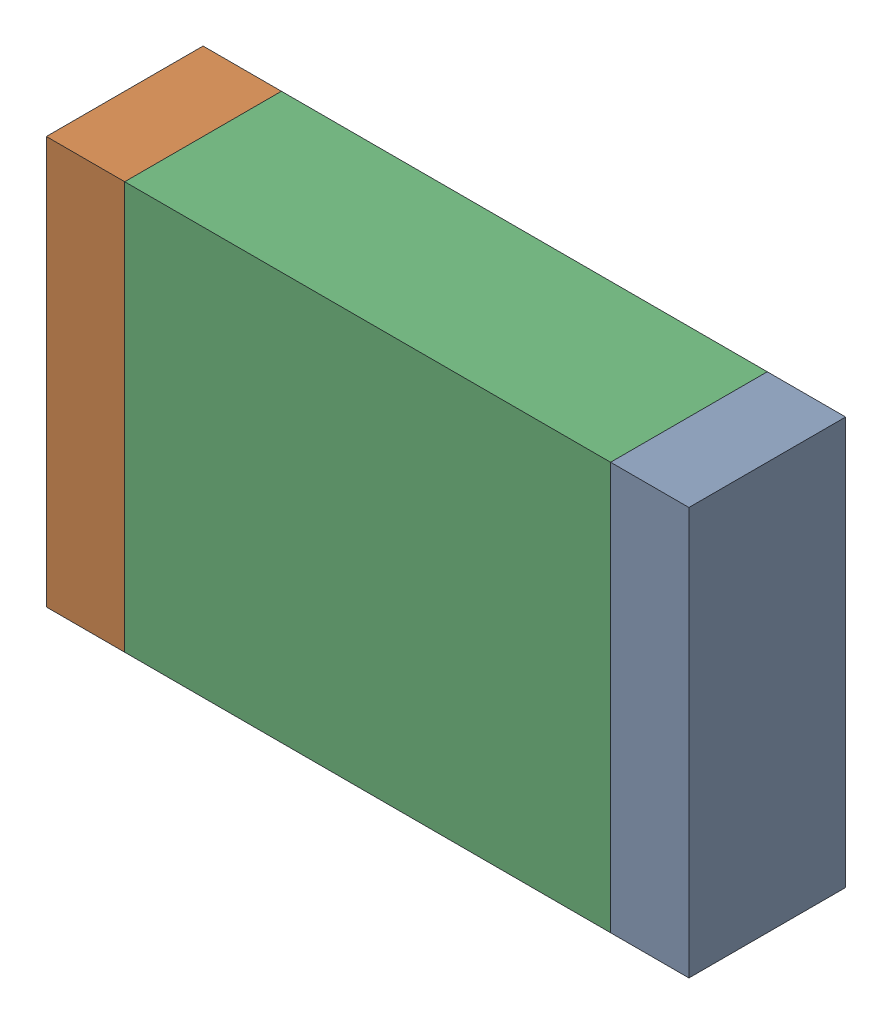
SolidWorks assembly C94, configuration Default. Lengths in mm.
Overall size (2.05 1.3 0.5).
6 component instances, 2 part files, 0 mates.
Components (placement in the parent):
- 836756336-1: 836756336 [Default] at (108.875 67.25 0) size (0.25 1.3 0.5)
  - Extruded_41-1: Extruded_41 [Default] at origin size (0.25 1.3 0.5)
- 836756336-2: 836756336 [Default] at (107.075 67.25 0) size (0.25 1.3 0.5)
  - Extruded_41-1: Extruded_41 [Default] at origin size (0.25 1.3 0.5)
- 836756464-1: 836756464 [Default] at (107.975 67.25 0) size (1.55 1.3 0.5)
  - Extruded_42-1: Extruded_42 [Default] at origin size (1.55 1.3 0.5)
